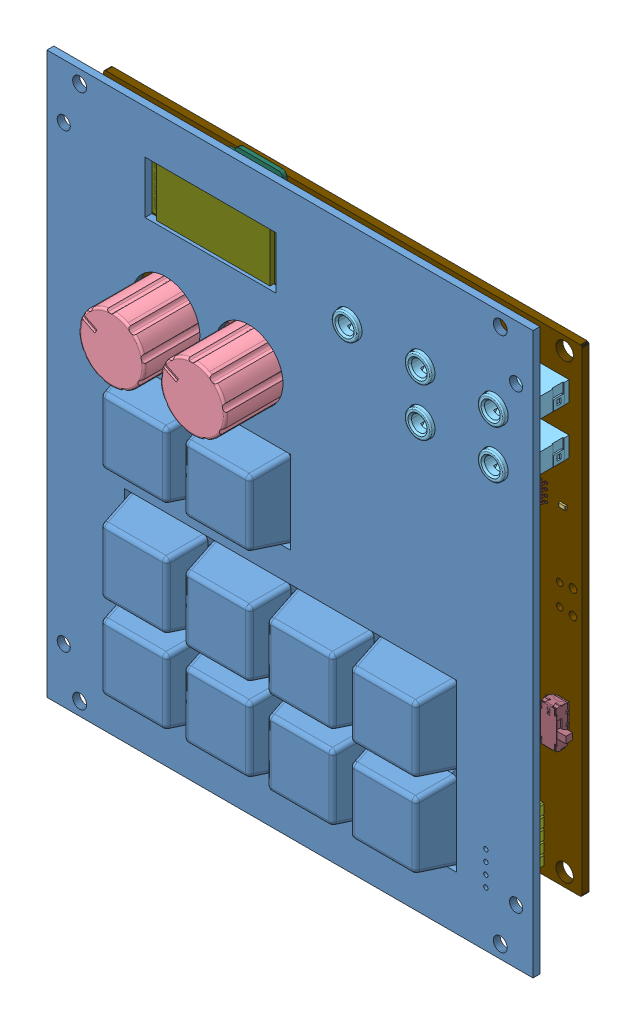
SolidWorks assembly dc31-badge, configuration Default. Lengths in mm.
Overall size (111.4 128.5 35.79).
126 component instances, 19 part files, 3 mates.
Components (placement in the parent):
- dc31.step-2: dc31.step [Default] at origin size (109.67 111.23 35.79)
  - MX_WithFlatCap.step-1: MX_WithFlatCap.step [Default] at (131.06 -111.73 7.63) x (-1 0 0) z (0 1 0) size (18 22.4 18)
    - COMPOUND.step-1: COMPOUND.step [Default] at origin size (18 22.4 18)
  - D_SOD-323.step-1: D_SOD-323.step [Default] at (123.7875 -60.54 1.63) x (-1 0 0) z (0 0 1) size (2.5 1.25 1.1)
    - SOLID.step-1: SOLID.step [Default] at origin size (2.5 1.25 1.1)
  - R_0603_1608Metric.step-1: R_0603_1608Metric.step [Default] at (196.19 -44.98 1.63) x (-1 0 0) z (0 0 1) size (1.6 0.8 0.45)
    - SOLID-0.step-1: SOLID-0.step [Default] at origin size (1.6 0.8 0.45)
  - Rotary_Encoder_With_Black_Knob.step-1: Rotary_Encoder_With_Black_Knob.step [Default] at (149.46 -76.86 2.13) size (15.12 15.21 30.51)
    - COMPOUND-1.step-1: COMPOUND-1.step [Default] at origin size (15.12 15.21 30.51)
  - R_0603_1608Metric.step-2: R_0603_1608Metric.step [Default] at (109.45 -92.99 1.63) size (1.6 0.8 0.45)
    - SOLID-0.step-1: SOLID-0.step [Default] at origin size (1.6 0.8 0.45)
  - STX-3790-5N_rA5.step-1: STX-3790-5N_rA5.step [Default] at (182.33 -64.52 12.13) size (9.3 6 15.5)
    - SOLID-2.step-1: SOLID-2.step [Default] at origin size (9.3 6 15.5)
  - C_0805_2012Metric.step-1: C_0805_2012Metric.step [Default] at (101.59 -90.75 1.63) size (2 1.25 1.25)
    - SOLID-3.step-1: SOLID-3.step [Default] at origin size (2 1.25 1.25)
  - D_SOD-323.step-2: D_SOD-323.step [Default] at (142.7375 -108.38 1.63) x (-1 0 0) z (0 0 1) size (2.5 1.25 1.1)
    - SOLID.step-1: SOLID.step [Default] at origin size (2.5 1.25 1.1)
  - PinHeader_1x05_P2.54mm_Vertical.step-1: PinHeader_1x05_P2.54mm_Vertical.step [Default] at (197.07 -137.1396 1.63) size (2.54 12.7 11.54)
    - SOLID-4.step-1: SOLID-4.step [Default] at origin size (2.54 12.7 11.54)
  - D_SOD-323.step-3: D_SOD-323.step [Default] at (111.02 -100.41 1.63) x (-1 0 0) z (0 0 1) size (2.5 1.25 1.1)
    - SOLID.step-1: SOLID.step [Default] at origin size (2.5 1.25 1.1)
  - MX_WithFlatCap.step-2: MX_WithFlatCap.step [Default] at (188.21 -130.78 7.63) x (-1 0 0) z (0 1 0) size (18 22.4 18)
    - COMPOUND.step-1: COMPOUND.step [Default] at origin size (18 22.4 18)
  - D_SOD-323.step-4: D_SOD-323.step [Default] at (180.8375 -108.38 1.63) x (-1 0 0) z (0 0 1) size (2.5 1.25 1.1)
    - SOLID.step-1: SOLID.step [Default] at origin size (2.5 1.25 1.1)
  - SO-5_4.4x3.6mm_P1.27mm.step-1: SO-5_4.4x3.6mm_P1.27mm.step [Default] at (164.72 -44.32 1.63) x (-1 0 0) z (0 0 1) size (6.3 3.6 1.1)
    - SOLID-5.step-1: SOLID-5.step [Default] at origin size (6.3 3.6 1.1)
  - C_0603_1608Metric.step-1: C_0603_1608Metric.step [Default] at (158.57 -44.42 1.63) x (0 1 0) z (0 0 1) size (1.6 0.8 0.8)
    - SOLID-6.step-1: SOLID-6.step [Default] at origin size (1.6 0.8 0.8)
  - R_0603_1608Metric.step-3: R_0603_1608Metric.step [Default] at (164.66 -58.57 1.63) size (1.6 0.8 0.45)
    - SOLID-0.step-1: SOLID-0.step [Default] at origin size (1.6 0.8 0.45)
  - R_0603_1608Metric.step-4: R_0603_1608Metric.step [Default] at (196.15 -69.98 1.63) x (-1 0 0) z (0 0 1) size (1.6 0.8 0.45)
    - SOLID-0.step-1: SOLID-0.step [Default] at origin size (1.6 0.8 0.45)
  - SOT-23.step-1: SOT-23.step [Default] at (182.92 -72.29 1.63) x (0 -1 0) z (0 0 1) size (2.5 3 1.2)
    - SOLID-7.step-1: SOLID-7.step [Default] at origin size (2.5 3 1.2)
  - R_0603_1608Metric.step-5: R_0603_1608Metric.step [Default] at (202.825 -74.605 1.63) x (-1 0 0) z (0 0 1) size (1.6 0.8 0.45)
    - SOLID-0.step-1: SOLID-0.step [Default] at origin size (1.6 0.8 0.45)
  - SOIC-8_3.9x4.9mm_P1.27mm.step-1: SOIC-8_3.9x4.9mm_P1.27mm.step [Default] at (196.135 -73.955 1.63) size (6 4.9 1.75)
    - SOLID-8.step-1: SOLID-8.step [Default] at origin size (6 4.9 1.75)
  - MX_WithFlatCap.step-3: MX_WithFlatCap.step [Default] at (169.16 -130.78 7.63) x (-1 0 0) z (0 1 0) size (18 22.4 18)
    - COMPOUND.step-1: COMPOUND.step [Default] at origin size (18 22.4 18)
  - D_SOD-323.step-5: D_SOD-323.step [Default] at (123.6875 -148.88 1.63) x (-1 0 0) z (0 0 1) size (2.5 1.25 1.1)
    - SOLID.step-1: SOLID.step [Default] at origin size (2.5 1.25 1.1)
  - MX_WithFlatCap.step-4: MX_WithFlatCap.step [Default] at (169.16 -111.73 7.63) x (-1 0 0) z (0 1 0) size (18 22.4 18)
    - COMPOUND.step-1: COMPOUND.step [Default] at origin size (18 22.4 18)
  - L_Wuerth_MAPI-3015.step-1: L_Wuerth_MAPI-3015.step [Default] at (109.97 -96.98 1.63) x (0 -1 0) z (0 0 1) size (3 3 1.5)
    - SOLID-9.step-1: SOLID-9.step [Default] at origin size (3 3 1.5)
  - D_SOD-323.step-6: D_SOD-323.step [Default] at (142.76 -82.54 1.63) x (-1 0 0) z (0 0 1) size (2.5 1.25 1.1)
    - SOLID.step-1: SOLID.step [Default] at origin size (2.5 1.25 1.1)
  - STX-3790-5N_rA5.step-2: STX-3790-5N_rA5.step [Default] at (199.0641 -64.53 12.13) size (9.3 6 15.5)
    - SOLID-2.step-1: SOLID-2.step [Default] at origin size (9.3 6 15.5)
  - MX_WithFlatCap.step-5: MX_WithFlatCap.step [Default] at (150.11 -111.73 7.63) x (-1 0 0) z (0 1 0) size (18 22.4 18)
    - COMPOUND.step-1: COMPOUND.step [Default] at origin size (18 22.4 18)
  - STX-3790-5N_rA5.step-3: STX-3790-5N_rA5.step [Default] at (165.5759 -53.51 12.13) size (9.3 6 15.5)
    - SOLID-2.step-1: SOLID-2.step [Default] at origin size (9.3 6 15.5)
  - D_SOD-323.step-7: D_SOD-323.step [Default] at (195.24 -113.19 1.63) x (0 -1 0) z (0 0 1) size (2.5 1.25 1.1)
    - SOLID.step-1: SOLID.step [Default] at origin size (2.5 1.25 1.1)
  - C_0603_1608Metric.step-2: C_0603_1608Metric.step [Default] at (166.405 -74.59 1.63) x (-1 0 0) z (0 0 1) size (1.6 0.8 0.8)
    - SOLID-6.step-1: SOLID-6.step [Default] at origin size (1.6 0.8 0.8)
  - R_0603_1608Metric.step-6: R_0603_1608Metric.step [Default] at (166.405 -72.55 1.63) size (1.6 0.8 0.45)
    - SOLID-0.step-1: SOLID-0.step [Default] at origin size (1.6 0.8 0.45)
  - R_0603_1608Metric.step-7: R_0603_1608Metric.step [Default] at (190.16 -75.585 1.63) x (-1 0 0) z (0 0 1) size (1.6 0.8 0.45)
    - SOLID-0.step-1: SOLID-0.step [Default] at origin size (1.6 0.8 0.45)
  - R_0603_1608Metric.step-8: R_0603_1608Metric.step [Default] at (190.17 -71.995 1.63) size (1.6 0.8 0.45)
    - SOLID-0.step-1: SOLID-0.step [Default] at origin size (1.6 0.8 0.45)
  - R_0603_1608Metric.step-9: R_0603_1608Metric.step [Default] at (179.81 -44.98 1.63) size (1.6 0.8 0.45)
    - SOLID-0.step-1: SOLID-0.step [Default] at origin size (1.6 0.8 0.45)
  - MX_WithFlatCap.step-6: MX_WithFlatCap.step [Default] at (131.06 -130.78 7.63) x (-1 0 0) z (0 1 0) size (18 22.4 18)
    - COMPOUND.step-1: COMPOUND.step [Default] at origin size (18 22.4 18)
  - MX_WithFlatCap.step-7: MX_WithFlatCap.step [Default] at (131.06 -85.89 7.63) x (-1 0 0) z (0 1 0) size (18 22.4 18)
    - COMPOUND.step-1: COMPOUND.step [Default] at origin size (18 22.4 18)
  - D_SOD-323.step-8: D_SOD-323.step [Default] at (180.8375 -148.88 1.63) x (-1 0 0) z (0 0 1) size (2.5 1.25 1.1)
    - SOLID.step-1: SOLID.step [Default] at origin size (2.5 1.25 1.1)
  - STX-3790-5N_rA5.step-4: STX-3790-5N_rA5.step [Default] at (182.32 -53.51 12.13) size (9.3 6 15.5)
    - SOLID-2.step-1: SOLID-2.step [Default] at origin size (9.3 6 15.5)
  - JS102011SAQN.step-1: JS102011SAQN.step [Default] at (202.735 -116.77 1.83) x (0 1 0) z (1 0 0) size (9 4.3 7.5)
    - SOLID-10.step-1: SOLID-10.step [Default] at origin size (9 4.3 7.5)
  - D_SOD-323.step-9: D_SOD-323.step [Default] at (191.84 -44.98 1.63) size (2.5 1.25 1.1)
    - SOLID.step-1: SOLID.step [Default] at origin size (2.5 1.25 1.1)
  - D_SOD-323.step-10: D_SOD-323.step [Default] at (161.7875 -148.88 1.63) x (-1 0 0) z (0 0 1) size (2.5 1.25 1.1)
    - SOLID.step-1: SOLID.step [Default] at origin size (2.5 1.25 1.1)
  - Rotary_Encoder_With_Black_Knob.step-2: Rotary_Encoder_With_Black_Knob.step [Default] at (130.41 -76.86 1.73) size (15.12 15.21 30.51)
    - COMPOUND-1.step-1: COMPOUND-1.step [Default] at origin size (15.12 15.21 30.51)
  - R_0603_1608Metric.step-10: R_0603_1608Metric.step [Default] at (177.77 -74.02 1.63) x (0 -1 0) z (0 0 1) size (1.6 0.8 0.45)
    - SOLID-0.step-1: SOLID-0.step [Default] at origin size (1.6 0.8 0.45)
  - D_SOD-323.step-11: D_SOD-323.step [Default] at (123.6875 -108.38 1.63) x (-1 0 0) z (0 0 1) size (2.5 1.25 1.1)
    - SOLID.step-1: SOLID.step [Default] at origin size (2.5 1.25 1.1)
  - D_SOD-323.step-12: D_SOD-323.step [Default] at (184.18 -44.98 1.63) size (2.5 1.25 1.1)
    - SOLID.step-1: SOLID.step [Default] at origin size (2.5 1.25 1.1)
  - TSSOP-14_4.4x5mm_P0.65mm.step-1: TSSOP-14_4.4x5mm_P0.65mm.step [Default] at (172.3625 -73.37 1.63) x (-1 0 0) z (0 0 1) size (6.4 5 1)
    - SOLID-11.step-1: SOLID-11.step [Default] at origin size (6.4 5 1)
  - D_SOD-323.step-13: D_SOD-323.step [Default] at (123.69 -82.53 1.63) x (-1 0 0) z (0 0 1) size (2.5 1.25 1.1)
    - SOLID.step-1: SOLID.step [Default] at origin size (2.5 1.25 1.1)
  - MX_WithFlatCap.step-8: MX_WithFlatCap.step [Default] at (188.21 -111.73 7.63) x (-1 0 0) z (0 1 0) size (18 22.4 18)
    - COMPOUND.step-1: COMPOUND.step [Default] at origin size (18 22.4 18)
  - MicroSD.step-1: MicroSD.step [Default] at (133.74 -48.67 1.63) x (-1 0 0) z (0 1 0) size (14.7 2.45 16.8)
    - SOLID-12.step-1: SOLID-12.step [Default] at origin size (14.7 2.45 16.8)
  - OLED 128x32 Display.step-1: OLED 128x32 Display.step [Default] at (113.98 -53.38 10.63) size (38 12 11.2)
    - COMPOUND-13.step-1: COMPOUND-13.step [Default] at origin size (38 12 11.2)
  - C_0805_2012Metric.step-2: C_0805_2012Metric.step [Default] at (100 -96.11 1.63) x (0 -1 0) z (0 0 1) size (2 1.25 1.25)
    - SOLID-3.step-1: SOLID-3.step [Default] at origin size (2 1.25 1.25)
  - D_SOD-323.step-14: D_SOD-323.step [Default] at (142.7375 -148.88 1.63) x (-1 0 0) z (0 0 1) size (2.5 1.25 1.1)
    - SOLID.step-1: SOLID.step [Default] at origin size (2.5 1.25 1.1)
  - STX-3790-5N_rA5.step-5: STX-3790-5N_rA5.step [Default] at (199.0641 -53.51 12.13) size (9.3 6 15.5)
    - SOLID-2.step-1: SOLID-2.step [Default] at origin size (9.3 6 15.5)
  - D_SOD-323.step-15: D_SOD-323.step [Default] at (142.72 -60.58 1.63) x (-1 0 0) z (0 0 1) size (2.5 1.25 1.1)
    - SOLID.step-1: SOLID.step [Default] at origin size (2.5 1.25 1.1)
  - D_SOD-323.step-16: D_SOD-323.step [Default] at (161.7875 -108.38 1.63) x (-1 0 0) z (0 0 1) size (2.5 1.25 1.1)
    - SOLID.step-1: SOLID.step [Default] at origin size (2.5 1.25 1.1)
  - C_0805_2012Metric.step-3: C_0805_2012Metric.step [Default] at (105.79 -98.12 1.63) x (-1 0 0) z (0 0 1) size (2 1.25 1.25)
    - SOLID-3.step-1: SOLID-3.step [Default] at origin size (2 1.25 1.25)
  - MX_WithFlatCap.step-9: MX_WithFlatCap.step [Default] at (150.11 -130.78 7.63) x (-1 0 0) z (0 1 0) size (18 22.4 18)
    - COMPOUND.step-1: COMPOUND.step [Default] at origin size (18 22.4 18)
  - C_0603_1608Metric.step-3: C_0603_1608Metric.step [Default] at (133.705 -60.91 1.63) size (1.6 0.8 0.8)
    - SOLID-6.step-1: SOLID-6.step [Default] at origin size (1.6 0.8 0.8)
  - R_0603_1608Metric.step-11: R_0603_1608Metric.step [Default] at (183.77 -75.53 1.63) size (1.6 0.8 0.45)
    - SOLID-0.step-1: SOLID-0.step [Default] at origin size (1.6 0.8 0.45)
  - C_0603_1608Metric.step-4: C_0603_1608Metric.step [Default] at (190.16 -73.765 1.63) x (-1 0 0) z (0 0 1) size (1.6 0.8 0.8)
    - SOLID-6.step-1: SOLID-6.step [Default] at origin size (1.6 0.8 0.8)
  - MX_WithFlatCap.step-10: MX_WithFlatCap.step [Default] at (150.11 -85.89 7.63) x (-1 0 0) z (0 1 0) size (18 22.4 18)
    - COMPOUND.step-1: COMPOUND.step [Default] at origin size (18 22.4 18)
  - IDC-Header_2x05_P2.54mm_Vertical.step-1: IDC-Header_2x05_P2.54mm_Vertical.step [Default] at (105.5878 -117.7036 -0.05) x (-1 0 0) z (0 0 -1) size (9.1 20.36 12.1)
    - SOLID-14.step-1: SOLID-14.step [Default] at origin size (9.1 20.36 12.1)
  - dc31 PCB.step-1: dc31 PCB.step [Default] at origin size (109.67 109.49 1.58)
- dc31-front2.step-1: dc31-front2.step [Default] at (-0.0214 0.019 12.13) size (111.4 128.5 1.58)
  - dc31-front PCB.step-1: dc31-front PCB.step [Default] at origin size (111.4 128.5 1.58)
Mates (geometry in assembly coordinates):
- Coincident4: coincident: plane of dc31.step-2/STX-3790-5N_rA5.step-2/SOLID-2.step-1 through (194.8641 -64.53 12.13) normal (0 0 1); plane of dc31-front2.step-1/dc31-front PCB.step-1 through (152.15 -95.6 12.13) normal (0 0 -1)
- Width1: width: plane of dc31-front2.step-1/dc31-front PCB.step-1 through (207.85 -31.35 12.13) normal (1 0 0); plane of dc31.step-2/dc31 PCB.step-1 through (96.45 -159.85 12.13) normal (-1 0 0); plane of dc31-front2.step-1/dc31-front PCB.step-1 through (97.3136 -149.8464 0) normal (-1 0 0); plane of dc31.step-2/dc31 PCB.step-1 through (206.9864 -41.3536 0) normal (1 0 0)
- Width2: width anti-aligned: plane of dc31-front2.step-1/dc31-front PCB.step-1 through (96.45 -31.35 12.13) normal (0 1 0); plane of dc31.step-2/dc31 PCB.step-1 through (207.85 -159.85 12.13) normal (0 -1 0); plane of dc31-front2.step-1/dc31-front PCB.step-1 through (206.4864 -150.3464 0) normal (0 -1 0); plane of dc31.step-2/dc31 PCB.step-1 through (97.8136 -40.8536 0) normal (0 1 0)
